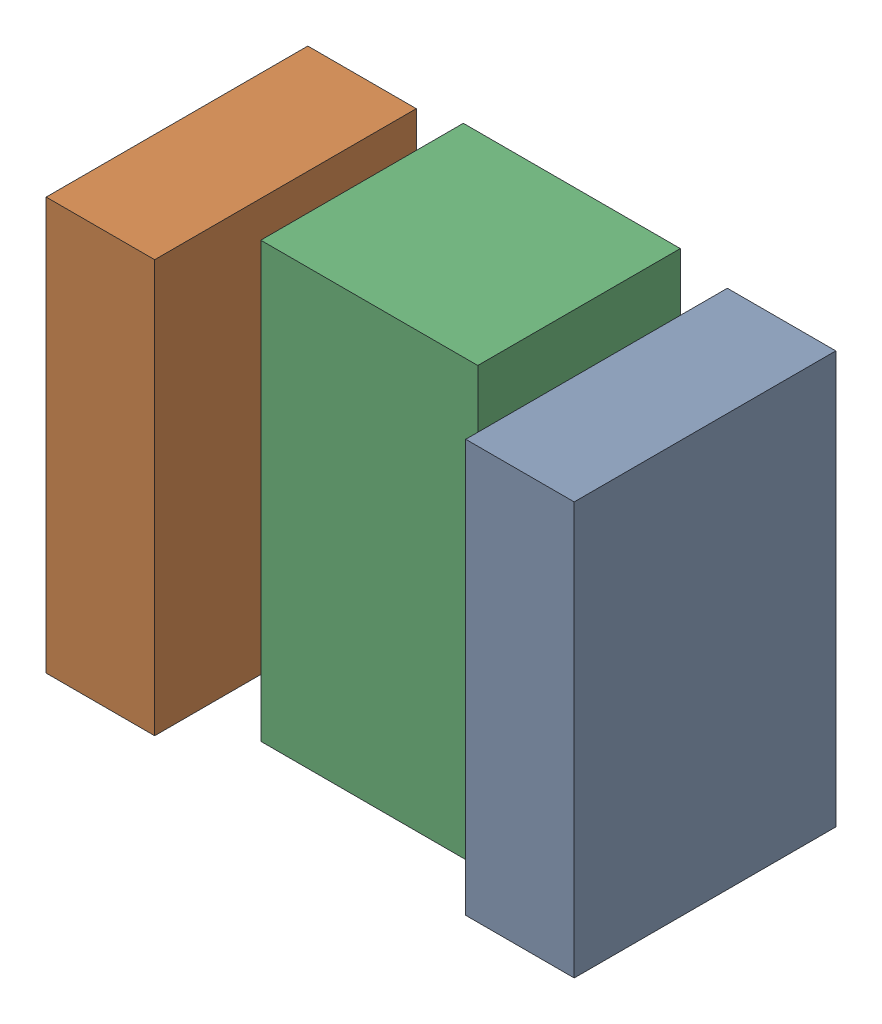
SolidWorks assembly C11_Motor_1Kanaloa_v2.0.0_Motor, configuration Default. Lengths in mm.
Overall size (3.65 3 1.81).
6 component instances, 2 part files, 0 mates.
Components (placement in the parent):
- 334788400-1: 334788400 [Default] at (78.936 53.086 0) size (0.75 2.85 1.81)
  - Extruded_5-1: Extruded_5 [Default] at origin size (0.75 2.85 1.81)
- 334788400-2: 334788400 [Default] at (76.036 53.086 0) size (0.75 2.85 1.81)
  - Extruded_5-1: Extruded_5 [Default] at origin size (0.75 2.85 1.81)
- 334788656-1: 334788656 [Default] at (77.486 53.086 0) size (1.5 3 1.4)
  - Extruded_1-1: Extruded_1 [Default] at origin size (1.5 3 1.4)
